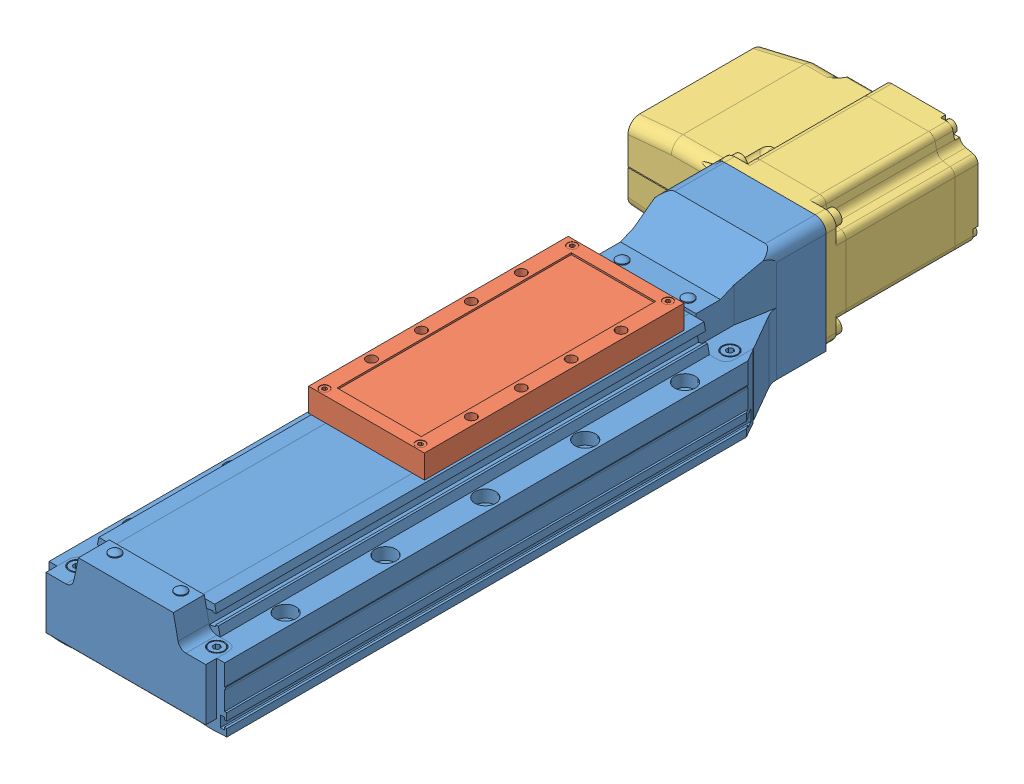
SolidWorks assembly LRT, configuration LRT0100xL-CT3A. Lengths in mm.
Overall size (120.76 58 399).
3 component instances, 3 part files, 3 mates.
Components (placement in the parent):
- LRT_base^LRT-1: LRT_base^LRT [LRT0100] at origin size (90 57.2 322.5) (virtual)
- LRT_carriage^LRT-1: LRT_carriage^LRT [LRT] at origin size (58 11.75 130) (virtual)
- NMS23_motor^LRT-1: NMS23_motor^LRT [LRT-T3A] at origin size (103.96 56.4 100.5) (virtual)
Mates (geometry in assembly coordinates):
- Coincident1: coincident aligned: plane of LRT_carriage^LRT-1 through (0 0 0) normal (0 1 0); plane of assembly through (0 0 0) normal (0 1 0)
- Coincident2: coincident aligned: plane of ? through (0 0 0) normal (1 0 0); plane of assembly through (0 0 0) normal (1 0 0)
- LimitDistance1: limit distance = 0 mm aligned: plane of ? through (0 0 0) normal (0 0 1); plane of assembly through (0 0 0) normal (0 0 1)
